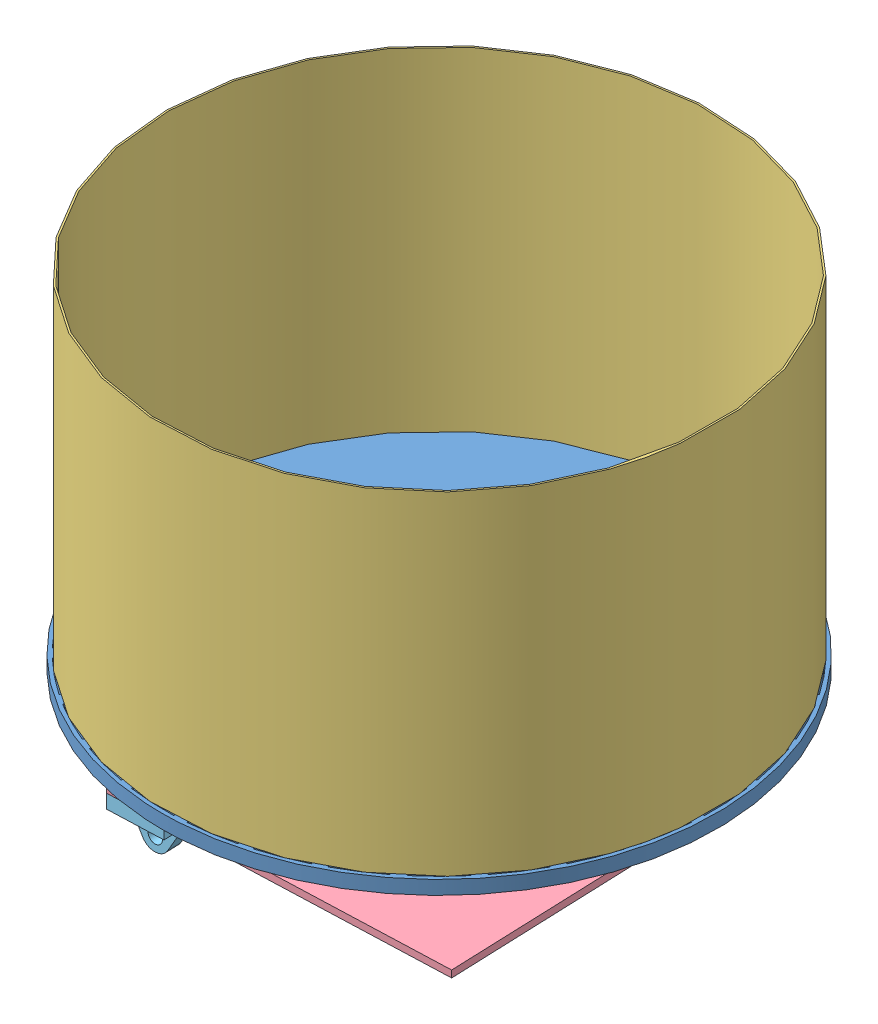
SolidWorks assembly Basketsubassembly1, configuration Default. Lengths in mm.
Overall size (299.41 227.3 299.41).
6 component instances, 5 part files, 13 mates.
Components (placement in the parent):
- Baskethubpt1wire-1: Baskethubpt1wire [Default] at (100.1689 237.7838 151.9941) size (254 6.35 254)
- Basketsupport-1: Basketsupport [Default] at (100.1689 194.6038 151.9941) x (0.999296 0 -0.037507) z (0.037507 0 0.999296) size (127 38.1 127)
- Basket-1: Basket [Default] at (100.1689 244.1338 151.9941) x (0.219644 0 -0.97558) z (0.97558 0 0.219644) size (250.51 152.4 250.51)
- DumpingPlate-1: DumpingPlate [Default] at (100.1689 193.0163 151.9941) x (0.999296 0 -0.037507) z (0.037507 0 0.999296) size (152.4 3.17 152.4)
- DumpingBracket-1: DumpingBracket [Default] at (39.0953 188.2538 217.8311) x (-0.999296 0 0.037507) z (0.037507 0 0.999296) size (25.4 22.2 25.4)
- DumpingBracket-2: DumpingBracket [Default] at (34.3319 188.2538 90.9205) x (-0.999296 0 0.037507) z (0.037507 0 0.999296) size (25.4 22.2 25.4)
Mates (geometry in assembly coordinates):
- Concentric1: concentric anti-aligned: cylinder of Baskethubpt1wire-1 through (100.1689 237.7838 151.9941) axis (0 1 0) radius 4.7625; cylinder of Basketsupport-1 through (100.1689 200.9538 151.9941) axis (0 -1 0) radius 4.826
- Distance1: distance = 5.08 mm anti-aligned: plane of Basketsupport-1 through (100.1689 232.7038 151.9941) normal (0 1 0); plane of Baskethubpt1wire-1 through (100.1689 237.7838 151.9941) normal (0 -1 0)
- Concentric2: concentric aligned: cylinder of Baskethubpt1wire-1 through (100.1689 244.1338 151.9941) axis (0 -1 0) radius 127; cylinder of Basket-1 through (100.1689 396.5338 151.9941) axis (0 -1 0) radius 125.2537
- Concentric3: concentric anti-aligned: cylinder of Basketsupport-1 through (100.1689 200.9538 151.9941) axis (0 -1 0) radius 4.826; cylinder of DumpingPlate-1 through (100.1689 191.4288 151.9941) axis (0 1 0) radius 4.826
- Coincident2: coincident anti-aligned: plane of DumpingPlate-1 through (179.1733 191.4288 225.2825) normal (0 -1 0); plane of DumpingBracket-2 through (47.4993 191.4288 103.1352) normal (0 1 0)
- Coincident3: coincident aligned: plane of DumpingPlate-1 through (26.8805 194.6038 230.9985) normal (-0.999296 0 0.037507); plane of DumpingBracket-2 through (22.1171 191.4288 104.0879) normal (-0.999296 0 0.037507)
- Coincident5: coincident anti-aligned: plane of DumpingPlate-1 through (179.1733 191.4288 225.2825) normal (0 -1 0); plane of DumpingBracket-1 through (52.2627 191.4288 230.0459) normal (0 1 0)
- Coincident6: coincident aligned: plane of DumpingPlate-1 through (26.8805 194.6038 230.9985) normal (-0.999296 0 0.037507); plane of DumpingBracket-1 through (26.8805 191.4288 230.9985) normal (-0.999296 0 0.037507)
- Coincident7: coincident anti-aligned: plane of Baskethubpt1wire-1 through (100.1689 244.1338 151.9941) normal (0 1 0); plane of Basket-1 through (100.1689 244.1338 151.9941) normal (0 -1 0)
- Concentric4: concentric aligned: circle of Basketsupport-1; cylinder of DumpingPlate-1 through (73.8341 191.4288 127.5647) axis (0 1 0) radius 2.8575
- Coincident8: coincident anti-aligned: plane of Basketsupport-1 through (100.1689 194.6038 151.9941) normal (0 -1 0); plane of DumpingPlate-1 through (179.1733 194.6038 225.2825) normal (0 1 0)
- Coincident9: coincident aligned: plane of DumpingPlate-1 through (103.0269 193.0163 228.1405) normal (0.037507 0 0.999296); plane of DumpingBracket-1 through (39.5716 188.2538 230.5222) normal (0.037507 0 0.999296)
- Coincident10: coincident aligned: plane of DumpingPlate-1 through (97.3108 193.0163 75.8477) normal (-0.037507 0 -0.999296); plane of DumpingBracket-2 through (33.8555 188.2538 78.2294) normal (-0.037507 0 -0.999296)
